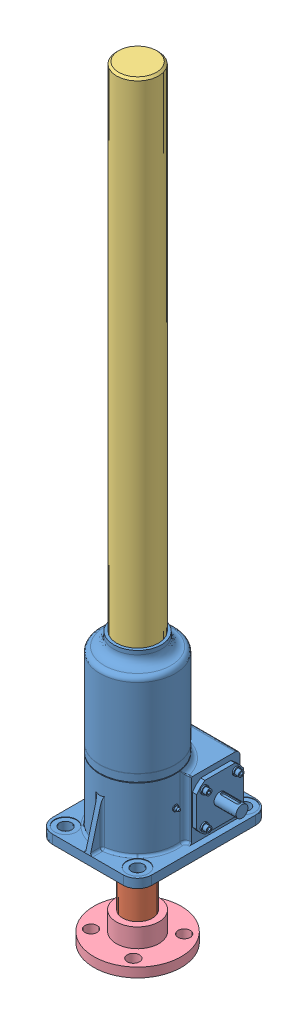
SolidWorks assembly EM20_BSJ_I_24_1_SSE_1_SSE_2_FP_1000_S, configuration Valor predeterminado. Lengths in mm.
4 component instances, 4 part files, 4 mates.
Components (placement in the parent):
- housing_I-SSE-SSE-1: housing_I-SSE-SSE [Valor predeterminado] at origin size (295.88 395.35 280.34)
- UILiftShaft_20-BSJ-I-1: UILiftShaft_20-BSJ-I [Valor predeterminado] at (0 1272.0598 0) x (0.783056 0 -0.621951) z (0 1 0) size (66 66 1467.1)
- UIStemCover_20-BSJ-I-1: UIStemCover_20-BSJ-I [Valor predeterminado] at (0 375.2735 0) x (1 0 0) z (0 1 0) size (89 89 1045)
- Top-Plate_20-BSJ-I-1: Top-Plate_20-BSJ-I [Valor predeterminado] at (0 -175.0404 0) x (0 1 0) z (-0.768397 0 0.639974) size (60 185 185)
Mates (geometry in assembly coordinates):
- Concêntrico1: concentric aligned: cylinder of housing_I-SSE-SSE-1 through (0 375.7735 0) axis (0 -1 0) radius 32.75; cylinder of UILiftShaft_20-BSJ-I-1 through (0 1272.0598 0) axis (0 -1 0) radius 31.5
- Coincidente1: coordinate: point of housing_I-SSE-SSE-1; point of assembly
- Concêntrico2: concentric aligned: cylinder of UILiftShaft_20-BSJ-I-1 through (0 1272.0598 0) axis (0 -1 0) radius 31.5; cylinder of Top-Plate_20-BSJ-I-1 through (0 -191.9999 0) axis (0 -1 0) radius 45
- Coincidente2: coincident anti-aligned: plane of UILiftShaft_20-BSJ-I-1 through (-19.5915 -135.0404 -24.6663) normal (0 -1 0); plane of Top-Plate_20-BSJ-I-1 through (-28.7988 -135.0404 -34.5779) normal (0 1 0)
